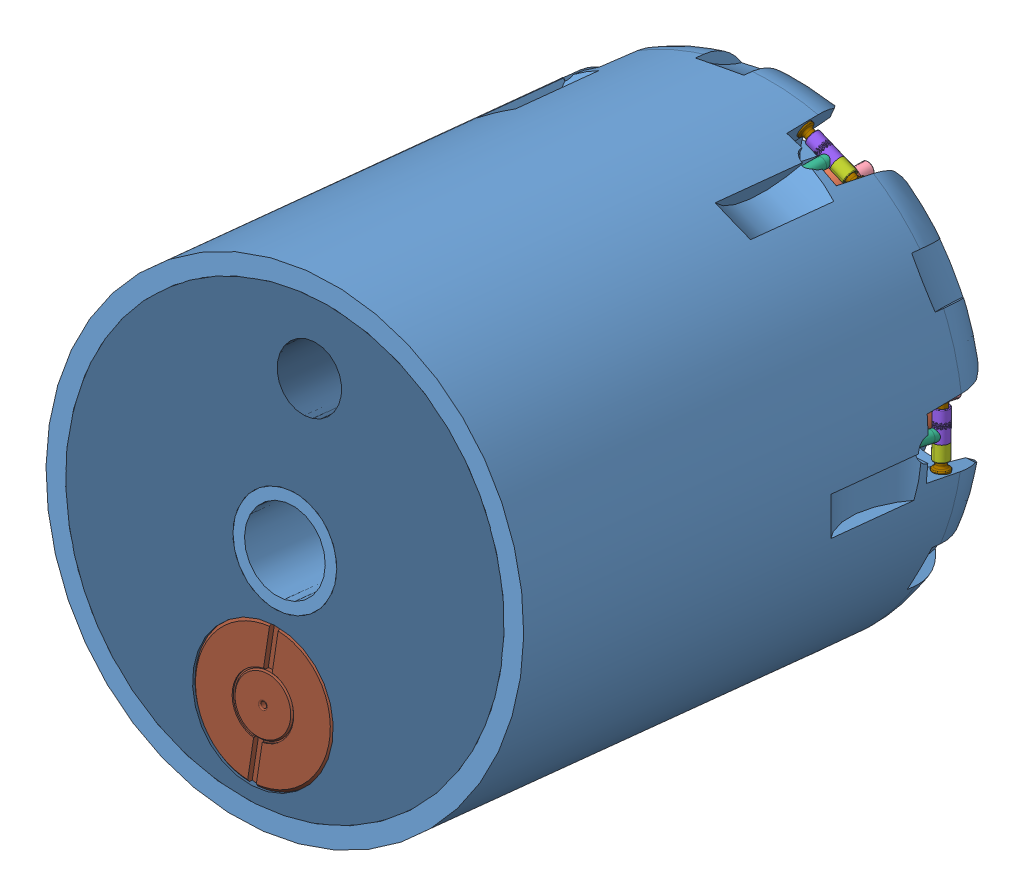
SolidWorks assembly Cylinder_Assem, configuration Default. Lengths in mm.
Overall size (69.66 89.82 81.22).
70 component instances, 11 part files, 20 mates.
Components (placement in the parent):
- Cylinder_CO2-1: Cylinder_CO2 [Default] at (-146.4417 -308.6249 -157.1733) x (0.207958 0.49803 0.841855) z (-0.922784 0.385318 0) size (60.74 55.75 42.2)
- Nippel and Plunger-2: Nippel and Plunger [Default] at (12.3136 -7.3586 -25.4776) x (0.381412 0.924405 0) z (0 0 -1) size (9.13 7.5 14.43)
  - CO2_Nippel_REAL-1: CO2_Nippel_REAL [Default] at (3.7547 10.0424 7.6011) size (7.5 7.5 12.44)
  - Spring-1: Spring [Default] at (3.7547 10.0424 12.2046) x (0.998867 -0.047582 0) z (0 0 1) size (1.72 1.98 3.45)
  - Plunger-6: Plunger [Default] at (3.7547 10.0424 21.7901) x (-1 0 0) z (0 0 -1) size (2 2.5 14.2)
  - Lock-4: Lock [Default] at (3.7547 10.0424 19.2511) x (0 -1 0) z (0 0 1) size (2 2.5 0.55)
  - Valve-1: Valve [Default] at (5.0051 10.0424 13.8011) x (0 0.006519 0.999979) z (1 0 0) size (3.31 2.12 4.24)
- Nippel and Plunger-3: Nippel and Plunger [Default] at (25.2421 -7.8371 -26.2743) x (0.985207 0.148692 0.085196) z (0.105825 -0.136848 -0.984923) size (9.13 7.5 14.43)
  - CO2_Nippel_REAL-1: CO2_Nippel_REAL [Default] at (3.7547 10.0424 7.6011) size (7.5 7.5 12.44)
  - Spring-1: Spring [Default] at (3.7547 10.0424 12.2046) x (0.998867 -0.047582 0) z (0 0 1) size (1.72 1.98 3.45)
  - Plunger-6: Plunger [Default] at (3.7547 10.0424 21.7901) x (-1 0 0) z (0 0 -1) size (2 2.5 14.2)
  - Lock-4: Lock [Default] at (3.7547 10.0424 19.2511) x (0 -1 0) z (0 0 1) size (2 2.5 0.55)
  - Valve-1: Valve [Default] at (5.0051 10.0424 13.8011) x (0 0.006519 0.999979) z (1 0 0) size (3.31 2.12 4.24)
- Nippel and Plunger-4: Nippel and Plunger [Default] at (24.6081 -29.8928 -22.6577) x (-0.352188 -0.871206 0.342001) z (-0.131786 -0.315611 -0.939693) size (9.13 7.5 14.43)
  - CO2_Nippel_REAL-1: CO2_Nippel_REAL [Default] at (3.7547 10.0424 7.6011) size (7.5 7.5 12.44)
  - Spring-1: Spring [Default] at (3.7547 10.0424 12.2046) x (0.998867 -0.047582 0) z (0 0 1) size (1.72 1.98 3.45)
  - Plunger-6: Plunger [Default] at (3.7547 10.0424 21.7901) x (-1 0 0) z (0 0 -1) size (2 2.5 14.2)
  - Lock-4: Lock [Default] at (3.7547 10.0424 19.2511) x (0 -1 0) z (0 0 1) size (2 2.5 0.55)
  - Valve-1: Valve [Default] at (5.0051 10.0424 13.8011) x (0 0.006519 0.999979) z (1 0 0) size (3.31 2.12 4.24)
- Nippel and Plunger-5: Nippel and Plunger [Default] at (31.4212 -19.1787 -24.8423) x (0.610564 -0.749195 0.256747) z (0.039932 -0.294654 -0.954769) size (9.13 7.5 14.43)
  - CO2_Nippel_REAL-1: CO2_Nippel_REAL [Default] at (3.7547 10.0424 7.6011) size (7.5 7.5 12.44)
  - Spring-1: Spring [Default] at (3.7547 10.0424 12.2046) x (0.998867 -0.047582 0) z (0 0 1) size (1.72 1.98 3.45)
  - Plunger-6: Plunger [Default] at (3.7547 10.0424 21.7901) x (-1 0 0) z (0 0 -1) size (2 2.5 14.2)
  - Lock-4: Lock [Default] at (3.7547 10.0424 19.2511) x (0 -1 0) z (0 0 1) size (2 2.5 0.55)
  - Valve-1: Valve [Default] at (5.0051 10.0424 13.8011) x (0 0.006519 0.999979) z (1 0 0) size (3.31 2.12 4.24)
- Nippel and Plunger-6: Nippel and Plunger [Default] at (11.6623 -29.4875 -21.8255) x (-0.962222 -0.091193 0.25654) z (-0.237612 -0.178762 -0.954769) size (9.13 7.5 14.43)
  - CO2_Nippel_REAL-1: CO2_Nippel_REAL [Default] at (3.7547 10.0424 7.6011) size (7.5 7.5 12.44)
  - Spring-1: Spring [Default] at (3.7547 10.0424 12.2046) x (0.998867 -0.047582 0) z (0 0 1) size (1.72 1.98 3.45)
  - Plunger-6: Plunger [Default] at (3.7547 10.0424 21.7901) x (-1 0 0) z (0 0 -1) size (2 2.5 14.2)
  - Lock-4: Lock [Default] at (3.7547 10.0424 19.2511) x (0 -1 0) z (0 0 1) size (2 2.5 0.55)
  - Valve-1: Valve [Default] at (5.0051 10.0424 13.8011) x (0 0.006519 0.999979) z (1 0 0) size (3.31 2.12 4.24)
- Nippel and Plunger-7: Nippel and Plunger [Default] at (5.6043 -18.2023 -23.2676) x (-0.596441 0.797927 0.087009) z (-0.171718 -0.020957 -0.984923) size (9.13 7.5 14.43)
  - CO2_Nippel_REAL-1: CO2_Nippel_REAL [Default] at (3.7547 10.0424 7.6011) size (7.5 7.5 12.44)
  - Spring-1: Spring [Default] at (3.7547 10.0424 12.2046) x (0.998867 -0.047582 0) z (0 0 1) size (1.72 1.98 3.45)
  - Plunger-6: Plunger [Default] at (3.7547 10.0424 21.7901) x (-1 0 0) z (0 0 -1) size (2 2.5 14.2)
  - Lock-4: Lock [Default] at (3.7547 10.0424 19.2511) x (0 -1 0) z (0 0 1) size (2 2.5 0.55)
  - Valve-1: Valve [Default] at (5.0051 10.0424 13.8011) x (0 0.006519 0.999979) z (1 0 0) size (3.31 2.12 4.24)
- Valve_Assem-1: Valve_Assem [Default] at (20.2827 -4.3999 -40.6087) x (-0.000119 -0.000286 -1) z (0.922784 -0.385318 0) size (1.3 1.3 3.88)
  - Tee-1-1: Tee-1 [Default] at (1.357 2.9038 0.6617) size (1.27 1.27 2.54)
  - Tee-2-1: Tee-2 [Default] at (1.357 2.9038 1.8619) x (1 -0.000954 0) z (0 0 1) size (1.3 1.42 5.08)
- Valve_Assem-2: Valve_Assem [Default] at (33.3645 -15.1556 -39.7474) x (0.10552 -0.136894 -0.98495) z (0.132766 -0.979672 0.150384) size (1.3 1.3 3.88)
  - Tee-1-1: Tee-1 [Default] at (1.357 2.9038 0.6617) size (1.27 1.27 2.54)
  - Tee-2-1: Tee-2 [Default] at (1.357 2.9038 1.8619) x (1 -0.000954 0) z (0 0 1) size (1.3 1.42 5.08)
- Valve_Assem-3: Valve_Assem [Default] at (30.6127 -31.6406 -36.8782) x (0.039742 -0.294422 -0.954849) z (-0.790017 -0.594354 0.150384) size (1.3 1.3 3.88)
  - Tee-1-1: Tee-1 [Default] at (1.357 2.9038 0.6617) size (1.27 1.27 2.54)
  - Tee-2-1: Tee-2 [Default] at (1.357 2.9038 1.8619) x (1 -0.000954 0) z (0 0 1) size (1.3 1.42 5.08)
- Valve_Assem-4: Valve_Assem [Default] at (14.7792 -37.3699 -34.8702) x (-0.131674 -0.315342 -0.939799) z (-0.922784 0.385318 0) size (1.3 1.3 3.88)
  - Tee-1-1: Tee-1 [Default] at (1.357 2.9038 0.6617) size (1.27 1.27 2.54)
  - Tee-2-1: Tee-2 [Default] at (1.357 2.9038 1.8619) x (1 -0.000954 0) z (0 0 1) size (1.3 1.42 5.08)
- Valve_Assem-5: Valve_Assem [Default] at (1.6974 -26.6142 -35.7314) x (-0.237313 -0.178734 -0.954849) z (-0.132766 0.979672 -0.150384) size (1.3 1.3 3.88)
  - Tee-1-1: Tee-1 [Default] at (1.357 2.9038 0.6617) size (1.27 1.27 2.54)
  - Tee-2-1: Tee-2 [Default] at (1.357 2.9038 1.8619) x (1 -0.000954 0) z (0 0 1) size (1.3 1.42 5.08)
- Valve_Assem-6: Valve_Assem [Default] at (4.4491 -10.1293 -38.6007) x (-0.171536 -0.021206 -0.98495) z (0.790017 0.594354 -0.150384) size (1.3 1.3 3.88)
  - Tee-1-1: Tee-1 [Default] at (1.357 2.9038 0.6617) size (1.27 1.27 2.54)
  - Tee-2-1: Tee-2 [Default] at (1.357 2.9038 1.8619) x (1 -0.000954 0) z (0 0 1) size (1.3 1.42 5.08)
- Rubber cuff-4: Rubber cuff [Default] at (36.6376 -16.8947 -40.5328) x (-0.309148 0.103226 0.945395) z (-0.132766 0.979672 -0.150384) size (1.44 1.44 1.99)
- Rubber cuff-5: Rubber cuff [Default] at (37.1031 -20.3297 -40.0055) x (0.978243 0.153924 0.139096) z (0.132766 -0.979672 0.150384) size (1.44 1.44 1.99)
- Rubber cuff-6: Rubber cuff [Default] at (23.2657 -2.4992 -41.9666) x (-0.080409 -0.192569 0.977984) z (-0.922784 0.385318 0) size (1.44 1.44 1.99)
- Rubber cuff-7: Rubber cuff [Default] at (4.1033 -6.6229 -39.9937) x (0.290757 -0.14727 0.945395) z (-0.790017 -0.594354 0.150384) size (1.44 1.44 1.99)
- Rubber cuff-8: Rubber cuff [Default] at (-1.6872 -25.142 -36.587) x (0.433183 0.193823 0.880219) z (0.132766 -0.979672 0.150384) size (1.44 1.44 1.99)
- Rubber cuff-9: Rubber cuff [Default] at (11.6847 -39.5376 -35.1532) x (0.204445 0.489617 0.84763) z (0.922784 -0.385318 0) size (1.44 1.44 1.99)
- Rubber cuff-10: Rubber cuff [Default] at (30.8471 -35.4139 -37.1261) x (-0.166721 0.444319 0.880219) z (0.790017 0.594354 -0.150384) size (1.44 1.44 1.99)
- Rubber cuff-11: Rubber cuff [Default] at (26.5012 -3.8502 -41.9666) x (0.384744 0.92141 0.05454) z (0.922784 -0.385318 0) size (1.44 1.44 1.99)
- Rubber cuff-12: Rubber cuff [Default] at (6.8732 -4.5389 -40.5209) x (-0.578303 0.803877 0.139096) z (0.790017 0.594354 -0.150384) size (1.44 1.44 1.99)
- Rubber cuff-13: Rubber cuff [Default] at (-2.1527 -21.7071 -37.1142) x (-0.947853 -0.081143 0.308207) z (-0.132766 0.979672 -0.150384) size (1.44 1.44 1.99)
- Rubber cuff-14: Rubber cuff [Default] at (8.4492 -38.1866 -35.1532) x (-0.354354 -0.848629 0.392762) z (-0.922784 0.385318 0) size (1.44 1.44 1.99)
- Rubber cuff-15: Rubber cuff [Default] at (28.0771 -37.4979 -36.5988) x (0.608694 -0.731095 0.308207) z (-0.790017 -0.594354 0.150384) size (1.44 1.44 1.99)
- Close of cylinder-1: Close of cylinder [Default] at (29.9825 -37.2022 18.5061) x (-0.997675 0.023558 0.063951) z (-0.06691 -0.16024 -0.984808) size (38 38 35.04)
  - Close of Cylinder-1: Close of Cylinder [Default] at (9.21 25.0211 10.7443) size (38 38 35.04)
  - Close Valve-1: Close Valve [Default] at (9.21 13.2711 11.5063) size (12.19 12.9 6.1)
Mates (geometry in assembly coordinates):
- Concentric1: concentric: circle of Cylinder_CO2-1; circle of Nippel and Plunger-2/CO2_Nippel_REAL-1
- Parallel1: parallel: plane of Cylinder_CO2-1 through (24.8784 -3.2886 -38.0786) normal (0 0 -1); plane of Nippel and Plunger-2/CO2_Nippel_REAL-1 through (23.0289 -7.718 -38.0786) normal (0 0 1)
- Distance1: distance = 0 mm: plane of Nippel and Plunger-2/CO2_Nippel_REAL-1 through (23.0289 -7.718 -38.0786) normal (0 0 1); plane of Cylinder_CO2-1 through (24.8784 -3.2886 -38.0786) normal (0 0 -1)
- Lock1: lock: unknown of Cylinder_CO2-1
- Concentric2: concentric: circle of Cylinder_CO2-1; circle of Nippel and Plunger-3/CO2_Nippel_REAL-1
- Distance2: distance = 0 mm: plane of Nippel and Plunger-3/CO2_Nippel_REAL-1 through (31.6284 -18.8384 -36.8535) normal (-0.105825 0.136848 0.984923); plane of Cylinder_CO2-1 through (34.6121 -15.0838 -37.0546) normal (0.105825 -0.136848 -0.984923)
- Concentric3: concentric: circle of Cylinder_CO2-1; circle of Nippel and Plunger-4/CO2_Nippel_REAL-1
- Distance3: distance = 0 mm: plane of Nippel and Plunger-4/CO2_Nippel_REAL-1 through (12.3198 -33.3648 -33.178) normal (0.131786 0.315611 0.939693); plane of Cylinder_CO2-1 through (14.0578 -29.2026 -34.8197) normal (-0.131786 -0.315611 -0.939693)
- Concentric4: concentric: circle of Cylinder_CO2-1; circle of Nippel and Plunger-5/CO2_Nippel_REAL-1
- Distance4: distance = 0 mm: plane of Nippel and Plunger-5/CO2_Nippel_REAL-1 through (26.2738 -31.6618 -34.4032) normal (-0.039932 0.294654 0.954769); plane of Cylinder_CO2-1 through (29.7926 -28.5038 -35.2306) normal (0.039932 -0.294654 -0.954769)
- Concentric5: concentric: circle of Cylinder_CO2-1; circle of Nippel and Plunger-6/CO2_Nippel_REAL-1
- Distance5: distance = 0 mm: plane of Nippel and Plunger-6/CO2_Nippel_REAL-1 through (3.7204 -22.2444 -34.4032) normal (0.237612 0.178762 0.954769); plane of Cylinder_CO2-1 through (3.4922 -17.5218 -35.2306) normal (-0.237612 -0.178762 -0.954769)
- Concentric6: concentric: circle of Cylinder_CO2-1; circle of Nippel and Plunger-7/CO2_Nippel_REAL-1
- Distance6: distance = 0 mm: plane of Nippel and Plunger-7/CO2_Nippel_REAL-1 through (9.0749 -9.421 -36.8535) normal (0.171718 0.020957 0.984923); plane of Cylinder_CO2-1 through (9.6472 -4.6595 -37.0546) normal (-0.171718 -0.020957 -0.984923)
- Parallel3: parallel: plane of Cylinder_CO2-1 through (-111.4314 -323.2439 -157.1733) normal (0.922784 -0.385318 0); plane of Valve_Assem-1/Tee-2-1 through (23.1196 -2.4382 -41.9666) normal (-0.922784 0.385318 0)
- Concentric7: concentric: circle of Cylinder_CO2-1; circle of Valve_Assem-1/Tee-2-1
- Concentric8: concentric: circle of Valve_Assem-2/Tee-2-1; circle of Rubber cuff-4
- Concentric9: concentric: circle of Valve_Assem-2/Tee-1-1; circle of Rubber cuff-5
- Concentric15: concentric: cylinder of Cylinder_CO2-1 through (18.0572 -19.6246 -29.9937) axis (0.06691 0.16024 0.984808) radius 19; cylinder of Close of cylinder-1/Close of Cylinder-1 through (18.0572 -19.6246 -29.9937) axis (0.06691 0.16024 0.984808) radius 19
- Distance7: distance = 0 mm: plane of Close of cylinder-1/Close of Cylinder-1 through (20.399 -14.0162 4.4746) normal (0.06691 0.16024 0.984808); plane of Cylinder_CO2-1 through (20.8637 -17.445 5.0009) normal (0.06691 0.16024 0.984808)
